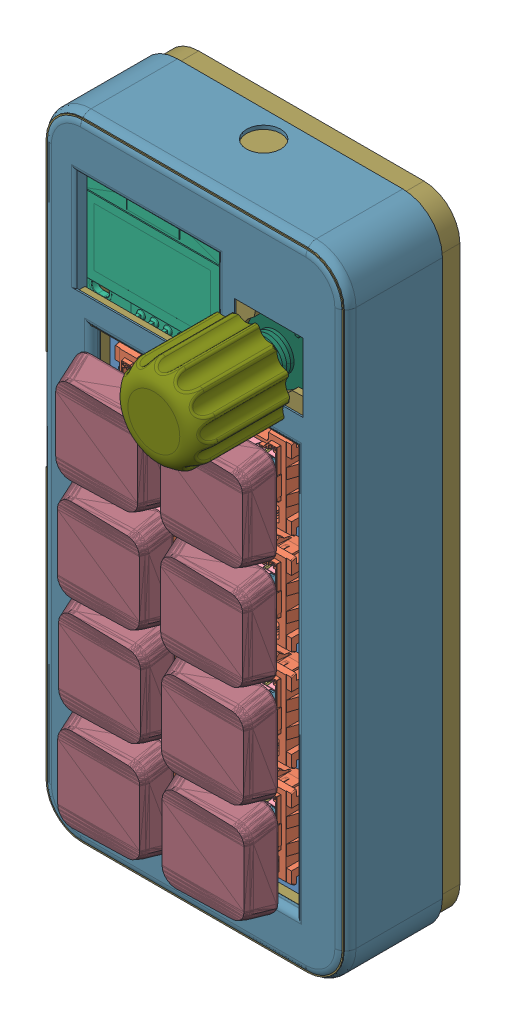
SolidWorks assembly Assem1flatSLDASM, configuration Default. Lengths in mm.
Overall size (57.58 119.94 39.83).
88 component instances, 18 part files, 37 mates.
Components (placement in the parent):
- MAin pad.step-1: MAin pad.step [Default] at (-246.3277 223.0029 -22.1276) size (47.5 109.86 1.6)
  - _autosave-MAin pad PCB.step-1: _autosave-MAin pad PCB.step [Default] at origin size (47.5 109.86 1.6)
- Kailh Polia.step-1: Kailh Polia.step [Default] at (-46.9377 130.2929 -15.6576) x (0 1 0) z (0 0 1) size (15.6 14.12 18.55)
  - Kailh Polia_1.step-1: Kailh Polia_1.step [Default] at origin size (15.6 14.12 18.55)
    - Housing.step-1: Housing.step [Default] at origin size (15.6 13.95 12.55)
    - ThickContact.step-1: ThickContact.step [Default] at origin size (1.42 6.81 10)
    - SpringContact.step-1: SpringContact.step [Default] at origin size (2.16 9.4 13.5)
    - Stem.step-1: Stem.step [Default] at origin size (6.51 8.7 13.55)
    - Lid.step-1: Lid.step [Default] at origin size (14.82 14.12 11.32) (hidden)
- Pantalla OLED 0.96'' 128x64.stp-2: Pantalla OLED 0.96'' 128x64.stp [Default] at (-47.1793 155.3868 -17.9876) x (-1 0 0) z (0 0 1) size (28.4 27.4 11)
  - STEP OLED Display 128x64.stp-1: STEP OLED Display 128x64.stp [Default] at origin size (28.4 27.4 11)
  - SOT-23_TOR.stp-1: SOT-23_TOR.stp [Default] at (-2.343 7.147 -0.01) x (-1 0 0) z (0 0 -1) size (2.9 2.79 1.3)
  - RES_CR16_MTK_1.stp-1: RES_CR16_MTK_1.stp [Default] at (6.1208 -0.3125 -0.01) x (0 -1 0) z (0 0 -1) size (1.7 0.89 0.56)
  - RES_CR16_MTK_1.stp-2: RES_CR16_MTK_1.stp [Default] at (4.2632 -0.3125 -0.01) x (0 -1 0) z (0 0 -1) size (1.7 0.89 0.56)
  - RES_CR16_MTK_1.stp-3: RES_CR16_MTK_1.stp [Default] at (2.4261 -0.3125 -0.01) x (0 -1 0) z (0 0 -1) size (1.7 0.89 0.56)
  - RES_CR16_MTK.stp-1: RES_CR16_MTK.stp [Default] at (7.9778 -0.3125 -0.01) x (0 -1 0) z (0 0 -1) size (1.7 0.89 0.56)
  - RES_CR16_MTK_1.stp-4: RES_CR16_MTK_1.stp [Default] at (8.5915 5.847 -0.01) x (-1 0 0) z (0 0 -1) size (1.7 0.89 0.56)
  - 0603.stp-1: 0603.stp [Default] at (12.274 -0.3047 -0.01) x (0 -1 0) z (0 0 -1) size (1.6 0.8 0.8)
  - 0603.stp-2: 0603.stp [Default] at (-6.7332 -0.3047 -0.81) x (0 1 0) z (0 0 1) size (1.6 0.8 0.8)
  - 0603.stp-3: 0603.stp [Default] at (10.0843 -0.3047 -0.01) x (0 -1 0) z (0 0 -1) size (1.6 0.8 0.8)
  - 0603.stp-4: 0603.stp [Default] at (-1.286 -0.3047 -0.01) x (0 -1 0) z (0 0 -1) size (1.6 0.8 0.8)
  - 0603.stp-5: 0603.stp [Default] at (-6.2037 7.0445 -0.81) x (0 1 0) z (0 0 1) size (1.6 0.8 0.8)
  - 0603.stp-6: 0603.stp [Default] at (-9.6955 -0.3047 -0.01) x (0 -1 0) z (0 0 -1) size (1.6 0.8 0.8)
  - 0603.stp-7: 0603.stp [Default] at (-12.1979 -0.3047 -0.01) x (0 -1 0) z (0 0 -1) size (1.6 0.8 0.8)
  - 0603.stp-8: 0603.stp [Default] at (-4.8316 -0.3047 -0.01) x (0 -1 0) z (0 0 -1) size (1.6 0.8 0.8)
  - SOD323F_DIO.stp-1: SOD323F_DIO.stp [Default] at (0.5718 -0.3099 -0.01) x (0 1 0) z (0 0 -1) size (2.5 0.75 0.82)
- Kailh Polia.step-2: Kailh Polia.step [Default] at (-27.8877 130.2929 -16.0276) x (0 1 0) z (0 0 1) size (15.6 14.12 18.55)
  - Kailh Polia_1.step-1: Kailh Polia_1.step [Default] at origin size (15.6 14.12 18.55)
    - Housing.step-1: Housing.step [Default] at origin size (15.6 13.95 12.55)
    - ThickContact.step-1: ThickContact.step [Default] at origin size (1.42 6.81 10)
    - SpringContact.step-1: SpringContact.step [Default] at origin size (2.16 9.4 13.5)
    - Stem.step-1: Stem.step [Default] at origin size (6.51 8.7 13.55)
    - Lid.step-1: Lid.step [Default] at origin size (14.82 14.12 11.32) (hidden)
- Bottom-1: Bottom [Default] at origin (suppressed, hidden)
- Copy of Part7^Assem1flatSLDASM-1: Copy of Part7^Assem1flatSLDASM [Default] at (0 0 -34.86) x (-1 0 0) z (0 0 -1) size (56.18 118.53 22.03)
- keycap_1u2-1: keycap_1u2 [Default] at (-132.8608 96.9906 -2.7978) x (0 1 0) z (0 0 -1) size (18.12 18.12 5.66)
- Top-1: Top [Default] at (0 0 -30.86) x (-1 0 0) z (0 0 -1) size (57.58 119.94 18.33)
- pec11r-4220k_l13-8_w12-4_h26-5.stp-1: pec11r-4220k_l13-8_w12-4_h26-5.stp [Default] at (-22.8298 152.6642 -20.5276) x (-1 0 0) z (0 1 0) size (13.86 30.2 14.85)
- Knob^Assem1flatSLDASM-1: Knob^Assem1flatSLDASM [Default] at (-22.8298 152.6642 5.9724) x (-1 0 0) z (0 0 1) size (17.24 17.12 17.56) (virtual)
- Kailh Polia.step-3: Kailh Polia.step [Default] at (-46.9377 111.2429 -16.0276) x (-0.000252 1 0) z (0 0 1) size (15.6 14.12 18.55)
  - Kailh Polia_1.step-1: Kailh Polia_1.step [Default] at origin size (15.6 14.12 18.55)
    - Housing.step-1: Housing.step [Default] at origin size (15.6 13.95 12.55)
    - ThickContact.step-1: ThickContact.step [Default] at origin size (1.42 6.81 10)
    - SpringContact.step-1: SpringContact.step [Default] at origin size (2.16 9.4 13.5)
    - Stem.step-1: Stem.step [Default] at origin size (6.51 8.7 13.55)
    - Lid.step-1: Lid.step [Default] at origin size (14.82 14.12 11.32) (hidden)
- Kailh Polia.step-4: Kailh Polia.step [Default] at (-27.8877 111.2429 -16.0276) x (0 1 0) z (0 0 1) size (15.6 14.12 18.55)
  - Kailh Polia_1.step-1: Kailh Polia_1.step [Default] at origin size (15.6 14.12 18.55)
    - Housing.step-1: Housing.step [Default] at origin size (15.6 13.95 12.55)
    - ThickContact.step-1: ThickContact.step [Default] at origin size (1.42 6.81 10)
    - SpringContact.step-1: SpringContact.step [Default] at origin size (2.16 9.4 13.5)
    - Stem.step-1: Stem.step [Default] at origin size (6.51 8.7 13.55)
    - Lid.step-1: Lid.step [Default] at origin size (14.82 14.12 11.32) (hidden)
- Kailh Polia.step-5: Kailh Polia.step [Default] at (-27.8877 73.1429 -16.0276) x (0 1 0) z (0 0 1) size (15.6 14.12 18.55)
  - Kailh Polia_1.step-1: Kailh Polia_1.step [Default] at origin size (15.6 14.12 18.55)
    - Housing.step-1: Housing.step [Default] at origin size (15.6 13.95 12.55)
    - ThickContact.step-1: ThickContact.step [Default] at origin size (1.42 6.81 10)
    - SpringContact.step-1: SpringContact.step [Default] at origin size (2.16 9.4 13.5)
    - Stem.step-1: Stem.step [Default] at origin size (6.51 8.7 13.55)
    - Lid.step-1: Lid.step [Default] at origin size (14.82 14.12 11.32) (hidden)
- Kailh Polia.step-6: Kailh Polia.step [Default] at (-46.9377 73.1429 -16.0276) x (0 1 0) z (0 0 1) size (15.6 14.12 18.55)
  - Kailh Polia_1.step-1: Kailh Polia_1.step [Default] at origin size (15.6 14.12 18.55)
    - Housing.step-1: Housing.step [Default] at origin size (15.6 13.95 12.55)
    - ThickContact.step-1: ThickContact.step [Default] at origin size (1.42 6.81 10)
    - SpringContact.step-1: SpringContact.step [Default] at origin size (2.16 9.4 13.5)
    - Stem.step-1: Stem.step [Default] at origin size (6.51 8.7 13.55)
    - Lid.step-1: Lid.step [Default] at origin size (14.82 14.12 11.32) (hidden)
- Kailh Polia.step-7: Kailh Polia.step [Default] at (-27.8877 92.1929 -16.0276) x (0 1 0) z (0 0 1) size (15.6 14.12 18.55)
  - Kailh Polia_1.step-1: Kailh Polia_1.step [Default] at origin size (15.6 14.12 18.55)
    - Housing.step-1: Housing.step [Default] at origin size (15.6 13.95 12.55)
    - ThickContact.step-1: ThickContact.step [Default] at origin size (1.42 6.81 10)
    - SpringContact.step-1: SpringContact.step [Default] at origin size (2.16 9.4 13.5)
    - Stem.step-1: Stem.step [Default] at origin size (6.51 8.7 13.55)
    - Lid.step-1: Lid.step [Default] at origin size (14.82 14.12 11.32) (hidden)
- Kailh Polia.step-8: Kailh Polia.step [Default] at (-46.9377 92.1929 -16.0276) x (0 1 0) z (0 0 1) size (15.6 14.12 18.55)
  - Kailh Polia_1.step-1: Kailh Polia_1.step [Default] at origin size (15.6 14.12 18.55)
    - Housing.step-1: Housing.step [Default] at origin size (15.6 13.95 12.55)
    - ThickContact.step-1: ThickContact.step [Default] at origin size (1.42 6.81 10)
    - SpringContact.step-1: SpringContact.step [Default] at origin size (2.16 9.4 13.5)
    - Stem.step-1: Stem.step [Default] at origin size (6.51 8.7 13.55)
    - Lid.step-1: Lid.step [Default] at origin size (14.82 14.12 11.32) (hidden)
- keycap_1u2-2: keycap_1u2 [Default] at (-132.9038 77.4454 -3.1392) x (-0.000252 1 0) z (0 0 -1) size (18.12 18.12 5.66)
- keycap_1u2-3: keycap_1u2 [Default] at (-113.4327 97.4021 -3.1678) x (0 1 0) z (0 0 -1) size (18.12 18.12 5.66)
- keycap_1u2-4: keycap_1u2 [Default] at (-132.7014 58.9821 -3.1678) x (0 1 0) z (0 0 -1) size (18.12 18.12 5.66)
- keycap_1u2-5: keycap_1u2 [Default] at (-132.8541 39.9075 -3.1678) x (0 1 0) z (0 0 -1) size (18.12 18.12 5.66)
- keycap_1u2-6: keycap_1u2 [Default] at (-113.392 77.8441 -3.1678) x (0 1 0) z (0 0 -1) size (18.12 18.12 5.66)
- keycap_1u2-8: keycap_1u2 [Default] at (-113.2519 58.6399 -3.1678) x (0 1 0) z (0 0 -1) size (18.12 18.12 5.66)
- keycap_1u2-9: keycap_1u2 [Default] at (-113.1409 39.7991 -3.1678) x (0 1 0) z (0 0 -1) size (18.12 18.12 5.66)
Mates (geometry in assembly coordinates):
- Concentric2: concentric anti-aligned: cylinder of MAin pad.step-1/_autosave-MAin pad PCB.step-1 through (-46.9377 130.2929 -22.9276) axis (0 0 1) radius 2; cylinder of Kailh Polia.step-1/Kailh Polia_1.step-1/Housing.step-1 through (-46.9377 130.2929 -20.1576) axis (0 0 -1) radius 1.925
- Coincident9: coincident anti-aligned: plane of MAin pad.step-1/_autosave-MAin pad PCB.step-1 through (-36.9047 114.4814 -20.5276) normal (0 0 1); plane of Kailh Polia.step-1/Kailh Polia_1.step-1/Housing.step-1 through (-43.5402 134.4699 -20.5276) normal (0 0 -1)
- Concentric3: concentric anti-aligned: cylinder of MAin pad.step-1/_autosave-MAin pad PCB.step-1 through (-41.8577 130.2929 -22.9276) axis (0 0 1) radius 0.85; cylinder of Kailh Polia.step-1/Kailh Polia_1.step-1/Housing.step-1 through (-41.8577 130.2929 -20.1576) axis (0 0 -1) radius 0.65
- Coincident19: coincident anti-aligned: plane of Kailh Polia.step-1/Kailh Polia_1.step-1/Stem.step-1 through (-46.9377 130.2929 -5.4076) normal (0 0 1); plane of keycap_1u2-1 through (-132.8608 96.9906 -5.4076) normal (0 0 -1)
- Coincident20: coincident anti-aligned: plane of Kailh Polia.step-1/Kailh Polia_1.step-1/Stem.step-1 through (-44.9377 130.8429 -5.4076) normal (1 0 0); plane of keycap_1u2-1 through (-44.9377 96.9906 -2.7978) normal (-1 0 0)
- InPlace1: in place: plane of Bottom-1 through (-58.1937 62.0139 -34.86) normal (0 0 -1); plane of Copy of Part7^Assem1flatSLDASM-1 through (0 0 -34.86) normal (0 0 -1); moOrthogonalPlaneRef_w of Bottom-1 through (-58.1937 62.0139 -34.86) normal (0 0 -1); plane of Copy of Part7^Assem1flatSLDASM-1 through (0 0 -34.86) normal (0 1 0); plane of Bottom-1 through (-58.1937 62.0139 -34.86) normal (0 0 -1); plane of Copy of Part7^Assem1flatSLDASM-1 through (0 0 -34.86) normal (-1 0 0); plane of Bottom-1 through (-58.1937 62.0139 -30.86) normal (0 0 -1); unknown of Top-1
- Coincident21: coincident aligned: plane of Bottom-1; plane of Top-1
- Coincident22: coincident aligned: moOrthogonalPlaneRef_w of Part6^Assem1flatSLDASM-1 through (0 0 -30.86) normal (0 1 0); plane of Top-1 through (0 0 -30.86) normal (0 1 0)
- Coincident23: coincident anti-aligned: moOrthogonalPlaneRef_w of Part6^Assem1flatSLDASM-1 through (0 0 -30.86) normal (1 0 0); plane of Top-1 through (0 0 -30.86) normal (-1 0 0)
- Coincident22: coincident anti-aligned: plane of MAin pad.step-1/_autosave-MAin pad PCB.step-1 through (-36.9047 114.4814 -20.5276) normal (0 0 1); plane of pec11r-4220k_l13-8_w12-4_h26-5.stp-1 through (-22.8298 152.6642 -20.5276) normal (0 0 -1)
- InPlace3: in place: plane of pec11r-4220k_l13-8_w12-4_h26-5.stp-1 through (-22.8298 152.6642 5.9724) normal (0 0 1); plane of ? through (0 0 5.9724) normal (0 0 1); plane of pec11r-4220k_l13-8_w12-4_h26-5.stp-1 through (-22.8298 152.6642 5.9724) normal (0 0 1); plane of ? through (0 0 5.9724) normal (0 1 0); plane of pec11r-4220k_l13-8_w12-4_h26-5.stp-1 through (-22.8298 152.6642 5.9724) normal (0 0 1); plane of ? through (0 0 5.9724) normal (1 0 0); plane of pec11r-4220k_l13-8_w12-4_h26-5.stp-1 through (-22.8298 152.6642 5.9724) normal (0 0 1); unknown of Knob^Assem1flatSLDASM-1
- Coincident26: coincident aligned: plane of pec11r-4220k_l13-8_w12-4_h26-5.stp-1; plane of Knob^Assem1flatSLDASM-1
- Coincident27: coincident aligned: moOrthogonalPlaneRef_w of pec11r-4220k_l13-8_w12-4_h26-5.stp-1 through (-22.8298 152.6642 5.9724) normal (0 -1 0); plane of Knob^Assem1flatSLDASM-1 through (-22.8298 152.6642 5.9724) normal (0 -1 0)
- Coincident28: coincident anti-aligned: moOrthogonalPlaneRef_w of pec11r-4220k_l13-8_w12-4_h26-5.stp-1 through (-22.8298 152.6642 5.9724) normal (1 0 0); plane of Knob^Assem1flatSLDASM-1 through (-22.8298 152.6642 5.9724) normal (-1 0 0)
- Concentric4: concentric anti-aligned: cylinder of MAin pad.step-1/_autosave-MAin pad PCB.step-1 through (-27.8877 130.2929 -22.9276) axis (0 0 1) radius 2; cylinder of Kailh Polia.step-2/Kailh Polia_1.step-1/Housing.step-1 through (-27.8877 130.2929 -20.5276) axis (0 0 -1) radius 1.925
- Coincident23: coincident anti-aligned: plane of MAin pad.step-1/_autosave-MAin pad PCB.step-1 through (-36.9047 114.4814 -20.5276) normal (0 0 1); plane of Kailh Polia.step-2/Kailh Polia_1.step-1/Housing.step-1 through (-27.8877 130.2699 -20.5276) normal (0 0 -1)
- Concentric5: concentric anti-aligned: circle of MAin pad.step-1/_autosave-MAin pad PCB.step-1; cylinder of Kailh Polia.step-3/Kailh Polia_1.step-1/Housing.step-1 through (-46.9377 111.2429 -20.5276) axis (0 0 -1) radius 1.925
- Coincident24: coincident anti-aligned: plane of MAin pad.step-1/_autosave-MAin pad PCB.step-1 through (-36.9047 114.4814 -20.5276) normal (0 0 1); plane of Kailh Polia.step-3/Kailh Polia_1.step-1/Housing.step-1 through (-46.9377 111.2199 -20.5276) normal (0 0 -1)
- Concentric6: concentric anti-aligned: cylinder of MAin pad.step-1/_autosave-MAin pad PCB.step-1 through (-27.8877 111.2429 -22.9276) axis (0 0 1) radius 2; cylinder of Kailh Polia.step-4/Kailh Polia_1.step-1/Housing.step-1 through (-27.8877 111.2429 -20.5276) axis (0 0 -1) radius 1.925
- Coincident25: coincident anti-aligned: plane of MAin pad.step-1/_autosave-MAin pad PCB.step-1 through (-36.9047 114.4814 -20.5276) normal (0 0 1); plane of Kailh Polia.step-4/Kailh Polia_1.step-1/Housing.step-1 through (-27.8877 111.2199 -20.5276) normal (0 0 -1)
- Concentric8: concentric anti-aligned: cylinder of MAin pad.step-1/_autosave-MAin pad PCB.step-1 through (-46.9377 92.1929 -22.9276) axis (0 0 1) radius 2; cone of Kailh Polia.step-8/Kailh Polia_1.step-1/Housing.step-1 through (-46.9377 92.1929 -23.279) axis (0 0 -1)
- Coincident26: coincident anti-aligned: plane of MAin pad.step-1/_autosave-MAin pad PCB.step-1 through (-36.9047 114.4814 -20.5276) normal (0 0 1); plane of Kailh Polia.step-8/Kailh Polia_1.step-1/Housing.step-1 through (-46.9377 92.1699 -20.5276) normal (0 0 -1)
- Concentric9: concentric aligned: circle of MAin pad.step-1/_autosave-MAin pad PCB.step-1; circle of Kailh Polia.step-7/Kailh Polia_1.step-1/Housing.step-1
- Coincident27: coincident anti-aligned: plane of MAin pad.step-1/_autosave-MAin pad PCB.step-1 through (-36.9047 114.4814 -20.5276) normal (0 0 1); plane of Kailh Polia.step-7/Kailh Polia_1.step-1/Housing.step-1 through (-27.8877 92.1699 -20.5276) normal (0 0 -1)
- Concentric10: concentric aligned: circle of MAin pad.step-1/_autosave-MAin pad PCB.step-1; circle of Kailh Polia.step-6/Kailh Polia_1.step-1/Housing.step-1
- Coincident28: coincident anti-aligned: plane of MAin pad.step-1/_autosave-MAin pad PCB.step-1 through (-36.9047 114.4814 -20.5276) normal (0 0 1); plane of Kailh Polia.step-6/Kailh Polia_1.step-1/Housing.step-1 through (-46.9377 73.1199 -20.5276) normal (0 0 -1)
- Concentric11: concentric aligned: circle of MAin pad.step-1/_autosave-MAin pad PCB.step-1; circle of Kailh Polia.step-5/Kailh Polia_1.step-1/Housing.step-1
- Coincident29: coincident anti-aligned: plane of MAin pad.step-1/_autosave-MAin pad PCB.step-1 through (-36.9047 114.4814 -20.5276) normal (0 0 1); plane of Kailh Polia.step-5/Kailh Polia_1.step-1/Housing.step-1 through (-27.8877 73.1199 -20.5276) normal (0 0 -1)
- Coincident34: coincident anti-aligned: plane of Kailh Polia.step-4/Kailh Polia_1.step-1/Stem.step-1 through (-28.4377 113.2429 -5.7776) normal (0 1 0); plane of keycap_1u2-6 through (-113.392 113.2429 -3.1678) normal (0 -1 0)
- Coincident35: coincident aligned: plane of Kailh Polia.step-4/Kailh Polia_1.step-1/Stem.step-1 through (-29.8877 110.6929 -5.7776) normal (-1 0 0); plane of keycap_1u2-6 through (-29.8877 77.8441 -3.1678) normal (-1 0 0)
- Coincident37: coincident anti-aligned: plane of Kailh Polia.step-4/Kailh Polia_1.step-1/Stem.step-1 through (-27.8877 111.2429 -5.7776) normal (0 0 1); plane of keycap_1u2-6 through (-113.392 77.8441 -5.7776) normal (0 0 -1)
- Coincident38: coincident anti-aligned: plane of Kailh Polia.step-3/Kailh Polia_1.step-1/Stem.step-1 through (-48.9375 110.6924 -5.7776) normal (-1 -0.000252 0); plane of keycap_1u2-2 through (-48.9292 77.4665 -3.1392) normal (1 0.000252 0)
- Coincident39: coincident anti-aligned: plane of Kailh Polia.step-2/Kailh Polia_1.step-1/Stem.step-1 through (-27.8877 130.2929 -5.7776) normal (0 0 1); plane of keycap_1u2-3 through (-113.4327 97.4021 -5.7776) normal (0 0 -1)
- Coincident40: coincident anti-aligned: plane of Kailh Polia.step-8/Kailh Polia_1.step-1/Stem.step-1 through (-46.9377 92.1929 -5.7776) normal (0 0 1); plane of keycap_1u2-4 through (-132.7014 58.9821 -5.7776) normal (0 0 -1)
- Coincident41: coincident anti-aligned: plane of Kailh Polia.step-7/Kailh Polia_1.step-1/Stem.step-1 through (-27.8877 92.1929 -5.7776) normal (0 0 1); plane of keycap_1u2-8 through (-113.2519 58.6399 -5.7776) normal (0 0 -1)
- Coincident42: coincident anti-aligned: plane of Kailh Polia.step-6/Kailh Polia_1.step-1/Stem.step-1 through (-46.9377 73.1429 -5.7776) normal (0 0 1); plane of keycap_1u2-5 through (-132.8541 39.9075 -5.7776) normal (0 0 -1)
- Coincident43: coincident anti-aligned: plane of Kailh Polia.step-5/Kailh Polia_1.step-1/Stem.step-1 through (-27.8877 73.1429 -5.7776) normal (0 0 1); plane of keycap_1u2-9 through (-113.1409 39.7991 -5.7776) normal (0 0 -1)
